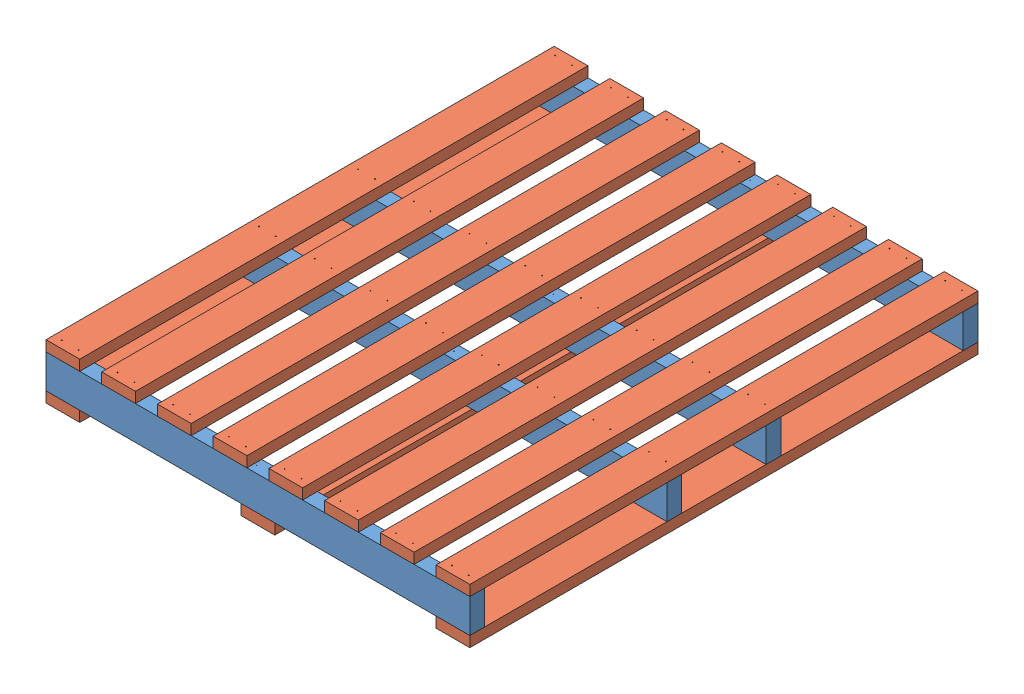
SolidWorks assembly PALLET, configuration Default. Lengths in mm.
Overall size (1005 130 1205).
15 component instances, 2 part files, 40 mates.
Components (placement in the parent):
- 1005-80-35 PART2-1: 1005-80-35 PART2 [Default] at (-310.488 1375.216 709.37) x (0 1 0) z (-1 0 0) size (80 35 1005)
- 1205-80-25 PART1-1: 1205-80-25 PART1 [Default] at (-522.6308 1455.216 -495.63) size (80 25 1205)
- 1205-80-25 PART1-2: 1205-80-25 PART1 [Default] at (-390.488 1455.216 -495.63) size (80 25 1205)
- 1205-80-25 PART1-3: 1205-80-25 PART1 [Default] at (-390.488 1350.216 -495.63) size (80 25 1205)
- 1205-80-25 PART1-4: 1205-80-25 PART1 [Default] at (-1315.488 1455.216 -495.63) size (80 25 1205)
- 1205-80-25 PART1-5: 1205-80-25 PART1 [Default] at (-1051.2022 1455.216 -495.63) size (80 25 1205)
- 1205-80-25 PART1-6: 1205-80-25 PART1 [Default] at (-919.0594 1455.216 -495.63) size (80 25 1205)
- 1205-80-25 PART1-7: 1205-80-25 PART1 [Default] at (-786.9165 1455.216 -495.63) size (80 25 1205)
- 1205-80-25 PART1-8: 1205-80-25 PART1 [Default] at (-654.7737 1455.216 -495.63) size (80 25 1205)
- 1205-80-25 PART1-9: 1205-80-25 PART1 [Default] at (-1183.3451 1455.216 -495.63) size (80 25 1205)
- 1205-80-25 PART1-11: 1205-80-25 PART1 [Default] at (-1315.488 1350.216 -495.63) size (80 25 1205)
- 1005-80-35 PART2-2: 1005-80-35 PART2 [Default] at (-310.488 1375.216 241.87) x (0 1 0) z (-1 0 0) size (80 35 1005)
- 1005-80-35 PART2-3: 1005-80-35 PART2 [Default] at (-310.488 1375.216 6.87) x (0 1 0) z (-1 0 0) size (80 35 1005)
- 1005-80-35 PART2-4: 1005-80-35 PART2 [Default] at (-310.488 1375.216 -460.63) x (0 1 0) z (-1 0 0) size (80 35 1005)
- 1205-80-25 PART1-12: 1205-80-25 PART1 [Default] at (-852.988 1350.216 -495.63) size (80 25 1205)
Mates (geometry in assembly coordinates):
- Parallel1: parallel aligned: plane of 1005-80-35 PART2-4 through (-1315.488 1375.216 -460.63) normal (0 0 1); plane of assembly through (0 0 10) normal (0 0 1)
- Parallel2: parallel aligned: plane of 1005-80-35 PART2-3 through (-1315.488 1375.216 6.87) normal (0 0 1); plane of assembly through (0 0 10) normal (0 0 1)
- Parallel3: parallel aligned: plane of 1005-80-35 PART2-2 through (-1315.488 1375.216 241.87) normal (0 0 1); plane of assembly through (0 0 10) normal (0 0 1)
- Parallel4: parallel aligned: plane of 1005-80-35 PART2-1 through (-1315.488 1375.216 709.37) normal (0 0 1); plane of assembly through (0 0 10) normal (0 0 1)
- Parallel5: parallel aligned: plane of 1005-80-35 PART2-2 through (-310.488 1375.216 241.87) normal (1 0 0); plane of assembly through (10 0 0) normal (1 0 0)
- Parallel6: parallel aligned: plane of 1005-80-35 PART2-1 through (-310.488 1375.216 709.37) normal (1 0 0); plane of assembly through (10 0 0) normal (1 0 0)
- Parallel7: parallel aligned: plane of 1005-80-35 PART2-3 through (-310.488 1375.216 6.87) normal (1 0 0); plane of assembly through (10 0 0) normal (1 0 0)
- Parallel8: parallel aligned: plane of 1005-80-35 PART2-4 through (-310.488 1375.216 -460.63) normal (1 0 0); plane of assembly through (10 0 0) normal (1 0 0)
- Parallel10: parallel aligned: plane of 1005-80-35 PART2-1 through (-1315.488 1375.216 709.37) normal (0 0 1); plane of 1205-80-25 PART1-4 through (-1315.488 1455.216 709.37) normal (0 0 1)
- Coincident15: coincident aligned: circle of 1005-80-35 PART2-1; circle of 1205-80-25 PART1-4
- Parallel16: parallel aligned: plane of 1205-80-25 PART1-4 through (-1315.488 1455.216 709.37) normal (-1 0 0); plane of 1005-80-35 PART2-2 through (-1315.488 1375.216 241.87) normal (-1 0 0)
- Parallel17: parallel aligned: plane of 1205-80-25 PART1-4 through (-1315.488 1455.216 709.37) normal (-1 0 0); plane of 1005-80-35 PART2-3 through (-1315.488 1375.216 6.87) normal (-1 0 0)
- Parallel18: parallel aligned: plane of 1205-80-25 PART1-4 through (-1315.488 1455.216 709.37) normal (-1 0 0); plane of 1005-80-35 PART2-4 through (-1315.488 1375.216 -460.63) normal (-1 0 0)
- Coincident21: coincident aligned: circle of 1205-80-25 PART1-4; circle of 1005-80-35 PART2-2
- Coincident23: coincident aligned: circle of 1205-80-25 PART1-4; circle of 1005-80-35 PART2-4
- Parallel19: parallel aligned: plane of 1005-80-35 PART2-1 through (-1315.488 1375.216 709.37) normal (0 0 1); plane of 1205-80-25 PART1-9 through (-1183.3451 1455.216 709.37) normal (0 0 1)
- Parallel20: parallel aligned: plane of 1005-80-35 PART2-1 through (-1315.488 1375.216 709.37) normal (0 0 1); plane of 1205-80-25 PART1-5 through (-1051.2022 1455.216 709.37) normal (0 0 1)
- Parallel21: parallel aligned: plane of 1005-80-35 PART2-1 through (-1315.488 1375.216 709.37) normal (0 0 1); plane of 1205-80-25 PART1-6 through (-919.0594 1455.216 709.37) normal (0 0 1)
- Parallel22: parallel aligned: plane of 1005-80-35 PART2-1 through (-1315.488 1375.216 709.37) normal (0 0 1); plane of 1205-80-25 PART1-7 through (-786.9165 1455.216 709.37) normal (0 0 1)
- Parallel23: parallel aligned: plane of 1005-80-35 PART2-1 through (-1315.488 1375.216 709.37) normal (0 0 1); plane of 1205-80-25 PART1-8 through (-654.7737 1455.216 709.37) normal (0 0 1)
- Parallel24: parallel aligned: plane of 1005-80-35 PART2-1 through (-1315.488 1375.216 709.37) normal (0 0 1); plane of 1205-80-25 PART1-8 through (-654.7737 1455.216 709.37) normal (0 0 1)
- Parallel25: parallel aligned: plane of 1005-80-35 PART2-1 through (-1315.488 1375.216 709.37) normal (0 0 1); plane of 1205-80-25 PART1-1 through (-522.6308 1455.216 709.37) normal (0 0 1)
- Parallel26: parallel aligned: plane of 1005-80-35 PART2-1 through (-1315.488 1375.216 709.37) normal (0 0 1); plane of 1205-80-25 PART1-2 through (-390.488 1455.216 709.37) normal (0 0 1)
- Coincident32: coincident aligned: circle of 1005-80-35 PART2-1; circle of 1205-80-25 PART1-9
- Coincident33: coincident aligned: circle of 1005-80-35 PART2-1; circle of 1205-80-25 PART1-5
- Coincident34: coincident aligned: circle of 1005-80-35 PART2-1; circle of 1205-80-25 PART1-6
- Parallel27: parallel aligned: plane of 1005-80-35 PART2-1 through (-1315.488 1375.216 709.37) normal (0 0 1); plane of 1205-80-25 PART1-7 through (-786.9165 1455.216 709.37) normal (0 0 1)
- Coincident38: coincident aligned: circle of 1005-80-35 PART2-1; circle of 1205-80-25 PART1-7
- Coincident39: coincident aligned: circle of 1205-80-25 PART1-4; circle of 1005-80-35 PART2-3
- Coincident40: coincident aligned: circle of 1005-80-35 PART2-1; circle of 1205-80-25 PART1-8
- Coincident41: coincident aligned: circle of 1005-80-35 PART2-1; circle of 1205-80-25 PART1-1
- Coincident42: coincident aligned: circle of 1005-80-35 PART2-1; circle of 1205-80-25 PART1-2
- Parallel28: parallel aligned: plane of 1005-80-35 PART2-1 through (-1315.488 1375.216 709.37) normal (0 0 1); plane of 1205-80-25 PART1-3 through (-390.488 1350.216 709.37) normal (0 0 1)
- Parallel29: parallel aligned: plane of 1005-80-35 PART2-1 through (-1315.488 1375.216 709.37) normal (0 0 1); plane of ? through (-840.8059 1236.6601 716.2286) normal (0 0 1)
- Parallel30: parallel aligned: plane of 1005-80-35 PART2-1 through (-1315.488 1375.216 709.37) normal (0 0 1); plane of 1205-80-25 PART1-11 through (-1315.488 1350.216 709.37) normal (0 0 1)
- Coincident46: coincident anti-aligned: circle of 1005-80-35 PART2-1; circle of 1205-80-25 PART1-11
- Coincident47: coincident anti-aligned: circle of 1005-80-35 PART2-1; circle of 1205-80-25 PART1-3
- Parallel32: parallel aligned: plane of 1005-80-35 PART2-4 through (-1315.488 1375.216 -495.63) normal (0 0 -1); plane of 1205-80-25 PART1-12 through (-852.988 1350.216 -495.63) normal (0 0 -1)
- Concentric8: concentric anti-aligned: circle of 1205-80-25 PART1-12; circle of 1005-80-35 PART2-4
- Coincident53: coincident anti-aligned: plane of 1005-80-35 PART2-4 through (-1315.488 1375.216 -460.63) normal (0 -1 0); plane of 1205-80-25 PART1-12 through (-852.988 1375.216 709.37) normal (0 1 0)
